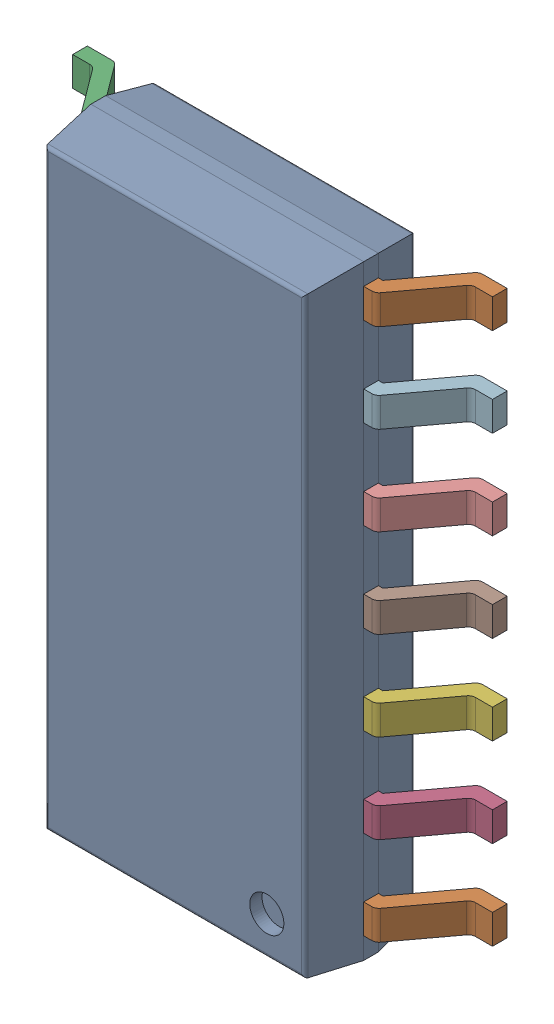
SolidWorks assembly IC11_IC104_1.step, configuration Default. Lengths in mm.
Overall size (6 8.65 1.75).
3 component instances, 2 part files, 0 mates.
Components (placement in the parent):
- 6348793888_1.step-3: 6348793888_1.step [Default] at (521.774 251.303 0) x (-1 0 0) z (0 0 1) size (6 8.65 1.75)
  - Body-16_1.step-14: Body-16_1.step [Default] at origin size (3.9 8.65 1.57)
  - PinsArrayLR-17_1.step-14: PinsArrayLR-17_1.step [Default] at origin size (6 8.04 1)
